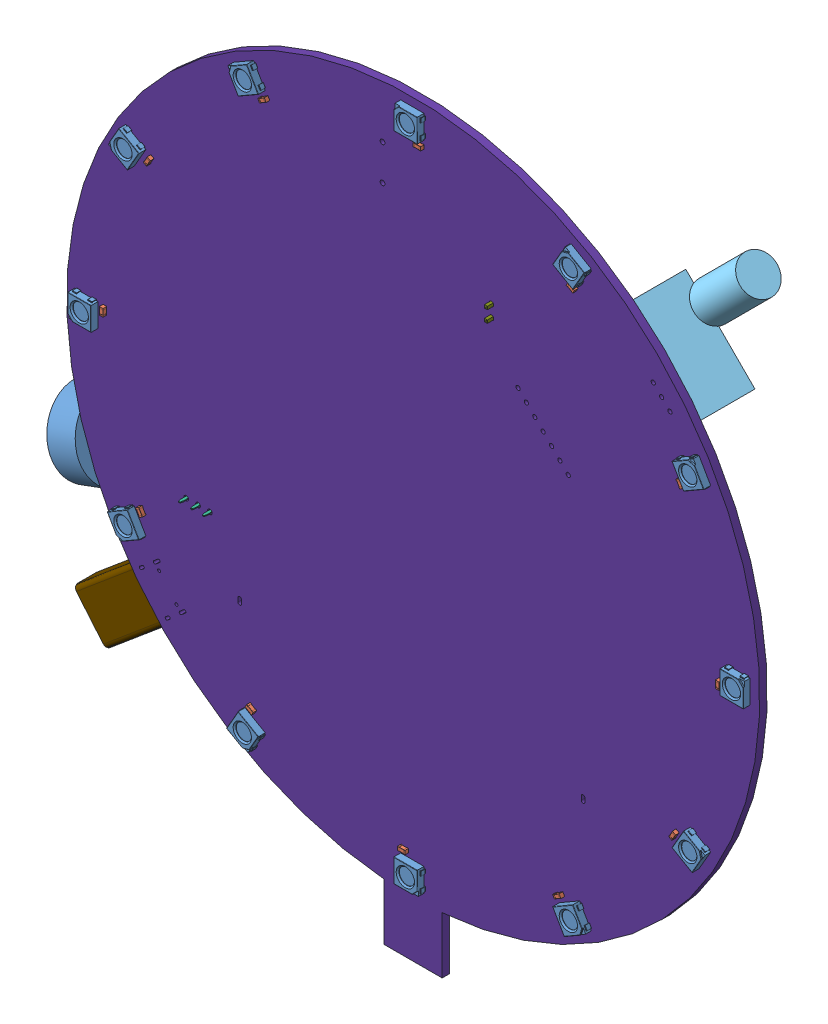
SolidWorks assembly Semafor_kompletni, configuration Výchozí. Lengths in mm.
Overall size (153.13 160.68 23.55).
171 component instances, 19 part files, 6 mates.
Components (placement in the parent):
- Semafor-1: Semafor [Výchozí] at origin size (148.79 160.68 22.8)
  - Semafor.step-1: Semafor.step [Výchozí] at origin size (148.79 160.68 22.8)
    - LED_WS2812B_PLCC4_5.0x5.0mm_P3.2mm.step-1: LED_WS2812B_PLCC4_5.0x5.0mm_P3.2mm.step [Výchozí] at (-39.4282 65.1 1.65) x (0.5 0.866025 0) z (0 0 1) size (5.4 5 1.6)
      - SOLID.step-1: SOLID.step [Výchozí] at origin size (5.4 5 1.6)
    - LED_WS2812B_PLCC4_5.0x5.0mm_P3.2mm.step-2: LED_WS2812B_PLCC4_5.0x5.0mm_P3.2mm.step [Výchozí] at (-30.05 100.1 1.65) x (0 1 0) z (0 0 1) size (5.4 5 1.6)
      - SOLID.step-1: SOLID.step [Výchozí] at origin size (5.4 5 1.6)
    - LED_WS2812B_PLCC4_5.0x5.0mm_P3.2mm.step-3: LED_WS2812B_PLCC4_5.0x5.0mm_P3.2mm.step [Výchozí] at (-170.05 100.1 1.65) x (0 -1 0) z (0 0 1) size (5.4 5 1.6)
      - SOLID.step-1: SOLID.step [Výchozí] at origin size (5.4 5 1.6)
    - C_0603_1608Metric.step-1: C_0603_1608Metric.step [Výchozí] at (-101.75 33.8 1.65) size (1.6 0.8 0.8)
      - SOLID-0.step-1: SOLID-0.step [Výchozí] at origin size (1.6 0.8 0.8)
    - C_0603_1608Metric.step-2: C_0603_1608Metric.step [Výchozí] at (-43.5875 65.6288 1.65) x (0.5 0.866025 0) z (0 0 1) size (1.6 0.8 0.8)
      - SOLID-0.step-1: SOLID-0.step [Výchozí] at origin size (1.6 0.8 0.8)
    - C_0603_1608Metric.step-3: C_0603_1608Metric.step [Výchozí] at (-134.4288 43.6125 1.65) x (0.866025 -0.5 0) z (0 0 1) size (1.6 0.8 0.8)
      - SOLID-0.step-1: SOLID-0.step [Výchozí] at origin size (1.6 0.8 0.8)
    - C_0603_1608Metric.step-4: C_0603_1608Metric.step [Výchozí] at (-166.15 101.75 1.65) x (0 -1 0) z (0 0 1) size (1.6 0.8 0.8)
      - SOLID-0.step-1: SOLID-0.step [Výchozí] at origin size (1.6 0.8 0.8)
    - LED_WS2812B_PLCC4_5.0x5.0mm_P3.2mm.step-4: LED_WS2812B_PLCC4_5.0x5.0mm_P3.2mm.step [Výchozí] at (-100.05 30.1 1.65) size (5.4 5 1.6)
      - SOLID.step-1: SOLID.step [Výchozí] at origin size (5.4 5 1.6)
    - C_0603_1608Metric.step-5: C_0603_1608Metric.step [Výchozí] at (-158.05 68.5 1.65) x (0.5 -0.866025 0) z (0 0 1) size (1.6 0.8 0.8)
      - SOLID-0.step-1: SOLID-0.step [Výchozí] at origin size (1.6 0.8 0.8)
    - C_0603_1608Metric.step-6: C_0603_1608Metric.step [Výchozí] at (-68.35 41.95 1.65) x (0.866025 0.5 0) z (0 0 1) size (1.6 0.8 0.8)
      - SOLID-0.step-1: SOLID-0.step [Výchozí] at origin size (1.6 0.8 0.8)
    - LED_WS2812B_PLCC4_5.0x5.0mm_P3.2mm.step-5: LED_WS2812B_PLCC4_5.0x5.0mm_P3.2mm.step [Výchozí] at (-100.05 170.1 1.65) x (-1 0 0) z (0 0 1) size (5.4 5 1.6)
      - SOLID.step-1: SOLID.step [Výchozí] at origin size (5.4 5 1.6)
    - LED_WS2812B_PLCC4_5.0x5.0mm_P3.2mm.step-6: LED_WS2812B_PLCC4_5.0x5.0mm_P3.2mm.step [Výchozí] at (-39.4282 135.1 1.65) x (-0.5 0.866025 0) z (0 0 1) size (5.4 5 1.6)
      - SOLID.step-1: SOLID.step [Výchozí] at origin size (5.4 5 1.6)
    - LED_WS2812B_PLCC4_5.0x5.0mm_P3.2mm.step-7: LED_WS2812B_PLCC4_5.0x5.0mm_P3.2mm.step [Výchozí] at (-160.6718 65.1 1.65) x (0.5 -0.866025 0) z (0 0 1) size (5.4 5 1.6)
      - SOLID.step-1: SOLID.step [Výchozí] at origin size (5.4 5 1.6)
    - LED_WS2812B_PLCC4_5.0x5.0mm_P3.2mm.step-8: LED_WS2812B_PLCC4_5.0x5.0mm_P3.2mm.step [Výchozí] at (-65.05 39.4782 1.65) x (0.866025 0.5 0) z (0 0 1) size (5.4 5 1.6)
      - SOLID.step-1: SOLID.step [Výchozí] at origin size (5.4 5 1.6)
    - C_0603_1608Metric.step-7: C_0603_1608Metric.step [Výchozí] at (-65.45 156.55 1.65) x (-0.866025 0.5 0) z (0 0 1) size (1.6 0.8 0.8)
      - SOLID-0.step-1: SOLID-0.step [Výchozí] at origin size (1.6 0.8 0.8)
    - C_0603_1608Metric.step-8: C_0603_1608Metric.step [Výchozí] at (-33.9 98.45 1.65) x (0 1 0) z (0 0 1) size (1.6 0.8 0.8)
      - SOLID-0.step-1: SOLID-0.step [Výchozí] at origin size (1.6 0.8 0.8)
    - C_0603_1608Metric.step-9: C_0603_1608Metric.step [Výchozí] at (-98.4 166.3 1.65) x (-1 0 0) z (0 0 1) size (1.6 0.8 0.8)
      - SOLID-0.step-1: SOLID-0.step [Výchozí] at origin size (1.6 0.8 0.8)
    - LED_WS2812B_PLCC4_5.0x5.0mm_P3.2mm.step-9: LED_WS2812B_PLCC4_5.0x5.0mm_P3.2mm.step [Výchozí] at (-160.6718 135.1 1.65) x (-0.5 -0.866025 0) z (0 0 1) size (5.4 5 1.6)
      - SOLID.step-1: SOLID.step [Výchozí] at origin size (5.4 5 1.6)
    - LED_WS2812B_PLCC4_5.0x5.0mm_P3.2mm.step-10: LED_WS2812B_PLCC4_5.0x5.0mm_P3.2mm.step [Výchozí] at (-65.05 160.7218 1.65) x (-0.866025 0.5 0) z (0 0 1) size (5.4 5 1.6)
      - SOLID.step-1: SOLID.step [Výchozí] at origin size (5.4 5 1.6)
    - C_0603_1608Metric.step-10: C_0603_1608Metric.step [Výchozí] at (-156.35 134.6 1.65) x (-0.5 -0.866025 0) z (0 0 1) size (1.6 0.8 0.8)
      - SOLID-0.step-1: SOLID-0.step [Výchozí] at origin size (1.6 0.8 0.8)
    - LED_WS2812B_PLCC4_5.0x5.0mm_P3.2mm.step-11: LED_WS2812B_PLCC4_5.0x5.0mm_P3.2mm.step [Výchozí] at (-135.05 160.7218 1.65) x (-0.866025 -0.5 0) z (0 0 1) size (5.4 5 1.6)
      - SOLID.step-1: SOLID.step [Výchozí] at origin size (5.4 5 1.6)
    - C_0603_1608Metric.step-11: C_0603_1608Metric.step [Výchozí] at (-131.65 158.3 1.65) x (-0.866025 -0.5 0) z (0 0 1) size (1.6 0.8 0.8)
      - SOLID-0.step-1: SOLID-0.step [Výchozí] at origin size (1.6 0.8 0.8)
    - C_0603_1608Metric.step-12: C_0603_1608Metric.step [Výchozí] at (-42.05 131.8 1.65) x (-0.5 0.866025 0) z (0 0 1) size (1.6 0.8 0.8)
      - SOLID-0.step-1: SOLID-0.step [Výchozí] at origin size (1.6 0.8 0.8)
    - LED_WS2812B_PLCC4_5.0x5.0mm_P3.2mm.step-12: LED_WS2812B_PLCC4_5.0x5.0mm_P3.2mm.step [Výchozí] at (-135.05 39.4782 1.65) x (0.866025 -0.5 0) z (0 0 1) size (5.4 5 1.6)
      - SOLID.step-1: SOLID.step [Výchozí] at origin size (5.4 5 1.6)
    - R_0603_1608Metric.step-1: R_0603_1608Metric.step [Výchozí] at (-119.75 147.925 -0.05) x (0 -1 0) z (0 0 -1) size (1.6 0.8 0.45)
      - SOLID-1.step-1: SOLID-1.step [Výchozí] at origin size (1.6 0.8 0.45)
    - R_0603_1608Metric.step-2: R_0603_1608Metric.step [Výchozí] at (-115.95 147.9 -0.05) x (0 -1 0) z (0 0 -1) size (1.6 0.8 0.45)
      - SOLID-1.step-1: SOLID-1.step [Výchozí] at origin size (1.6 0.8 0.45)
    - D_SOD-123.step-1: D_SOD-123.step [Výchozí] at (-130.0125 82.075 -0.05) x (-1 0 0) z (0 0 -1) size (3.8 1.6 1.25)
      - SOLID-2.step-1: SOLID-2.step [Výchozí] at origin size (3.8 1.6 1.25)
    - E22_900T22D.step-1: E22_900T22D.step [Výchozí] at (-60.45 137.7711 -0.05) x (-0.707107 -0.707107 0) z (0 0 -1) size (50 21 17.3)
      - SOLID-3.step-1: SOLID-3.step [Výchozí] at origin size (50 21 17.3)
    - D_SOD-123.step-2: D_SOD-123.step [Výchozí] at (-96.1 29.05 -0.05) x (0 -1 0) z (0 0 -1) size (3.8 1.6 1.25)
      - SOLID-2.step-1: SOLID-2.step [Výchozí] at origin size (3.8 1.6 1.25)
    - PinSocket_1x03_P2.54mm_Vertical.step-1: PinSocket_1x03_P2.54mm_Vertical.step [Výchozí] at (-143.675 75.375 -0.05) x (0 1 0) z (0 0 -1) size (2.54 7.62 10.1)
      - SOLID-4.step-1: SOLID-4.step [Výchozí] at origin size (2.54 7.62 10.1)
    - D_SOD-323.step-1: D_SOD-323.step [Výchozí] at (-142.6 58.8 -0.05) x (0.642788 -0.766044 0) z (0 0 -1) size (2.5 1.25 1.1)
      - SOLID-5.step-1: SOLID-5.step [Výchozí] at origin size (2.5 1.25 1.1)
    - C_0603_1608Metric.step-13: C_0603_1608Metric.step [Výchozí] at (-158.9591 131.0993 -0.05) x (-0.939693 0.34202 0) z (0 0 -1) size (1.6 0.8 0.8)
      - SOLID-0.step-1: SOLID-0.step [Výchozí] at origin size (1.6 0.8 0.8)
    - R_0603_1608Metric.step-3: R_0603_1608Metric.step [Výchozí] at (-83.3756 132.275 -0.05) x (-1 0 0) z (0 0 -1) size (1.6 0.8 0.45)
      - SOLID-1.step-1: SOLID-1.step [Výchozí] at origin size (1.6 0.8 0.45)
    - R_0603_1608Metric.step-4: R_0603_1608Metric.step [Výchozí] at (-118.05 147.9 -0.05) x (0 -1 0) z (0 0 -1) size (1.6 0.8 0.45)
      - SOLID-1.step-1: SOLID-1.step [Výchozí] at origin size (1.6 0.8 0.45)
    - R_0603_1608Metric.step-5: R_0603_1608Metric.step [Výchozí] at (-116.95 136.3 -0.05) x (0 -1 0) z (0 0 -1) size (1.6 0.8 0.45)
      - SOLID-1.step-1: SOLID-1.step [Výchozí] at origin size (1.6 0.8 0.45)
    - C_0805_2012Metric.step-1: C_0805_2012Metric.step [Výchozí] at (-152.9591 126.5493 -0.05) x (0.939693 -0.34202 0) z (0 0 -1) size (2 1.25 1.25)
      - SOLID-6.step-1: SOLID-6.step [Výchozí] at origin size (2 1.25 1.25)
    - LED_0603_1608Metric.step-1: LED_0603_1608Metric.step [Výchozí] at (-147.525 84.025 -0.05) x (-1 0 0) z (0 0 -1) size (1.6 0.8 1.1)
      - SOLID-7.step-1: SOLID-7.step [Výchozí] at origin size (1.6 0.8 1.1)
    - SOT-23.step-1: SOT-23.step [Výchozí] at (-83.3256 136.55 -0.05) x (0 1 0) z (0 0 -1) size (2.5 3 1.2)
      - SOLID-8.step-1: SOLID-8.step [Výchozí] at origin size (2.5 3 1.2)
    - SOT-23.step-2: SOT-23.step [Výchozí] at (-146.9091 122.0993 -0.05) x (0.939693 -0.34202 0) z (0 0 -1) size (2.5 3 1.2)
      - SOLID-8.step-1: SOLID-8.step [Výchozí] at origin size (2.5 3 1.2)
    - R_0603_1608Metric.step-6: R_0603_1608Metric.step [Výchozí] at (-120.725 43.975 -0.05) x (-1 0 0) z (0 0 -1) size (1.6 0.8 0.45)
      - SOLID-1.step-1: SOLID-1.step [Výchozí] at origin size (1.6 0.8 0.45)
    - C_0805_2012Metric.step-2: C_0805_2012Metric.step [Výchozí] at (-159.7591 129.0993 -0.05) x (-0.939693 0.34202 0) z (0 0 -1) size (2 1.25 1.25)
      - SOLID-6.step-1: SOLID-6.step [Výchozí] at origin size (2 1.25 1.25)
    - R_0603_1608Metric.step-7: R_0603_1608Metric.step [Výchozí] at (-120.15 136.3 -0.05) x (0 -1 0) z (0 0 -1) size (1.6 0.8 0.45)
      - SOLID-1.step-1: SOLID-1.step [Výchozí] at origin size (1.6 0.8 0.45)
    - D_SOD-323.step-2: D_SOD-323.step [Výchozí] at (-147.5 62.875 -0.05) x (-0.766044 -0.642788 0) z (0 0 -1) size (2.5 1.25 1.1)
      - SOLID-5.step-1: SOLID-5.step [Výchozí] at origin size (2.5 1.25 1.1)
    - C_0805_2012Metric.step-3: C_0805_2012Metric.step [Výchozí] at (-128.3875 78.75 -0.05) x (0 -1 0) z (0 0 -1) size (2 1.25 1.25)
      - SOLID-6.step-1: SOLID-6.step [Výchozí] at origin size (2 1.25 1.25)
    - R_0603_1608Metric.step-8: R_0603_1608Metric.step [Výchozí] at (-143.0091 117.4493 -0.05) x (0.939693 -0.34202 0) z (0 0 -1) size (1.6 0.8 0.45)
      - SOLID-1.step-1: SOLID-1.step [Výchozí] at origin size (1.6 0.8 0.45)
    - LED_0603_1608Metric.step-2: LED_0603_1608Metric.step [Výchozí] at (-109.425 43.2125 -0.05) x (0 -1 0) z (0 0 -1) size (1.6 0.8 1.1)
      - SOLID-7.step-1: SOLID-7.step [Výchozí] at origin size (1.6 0.8 1.1)
    - R_0603_1608Metric.step-9: R_0603_1608Metric.step [Výchozí] at (-135.1875 77.025 -0.05) x (0 1 0) z (0 0 -1) size (1.6 0.8 0.45)
      - SOLID-1.step-1: SOLID-1.step [Výchozí] at origin size (1.6 0.8 0.45)
    - USB_C.step-1: USB_C.step [Výchozí] at (-154.7 55.1 -0.05) x (-0.766044 -0.642788 0) z (0 0 -1) size (7.5 9 3.5)
      - SOLID-9.step-1: SOLID-9.step [Výchozí] at origin size (7.5 9 3.5)
    - Battery_pack.step-1: Battery_pack.step [Výchozí] at (-99.9 62.1 -0.05) x (-1 0 0) z (0 0 -1) size (77 21 19.5)
      - SOLID-10.step-1: SOLID-10.step [Výchozí] at origin size (77 21 19.5)
    - LED_0603_1608Metric.step-3: LED_0603_1608Metric.step [Výchozí] at (-107.575 43.225 -0.05) x (0 -1 0) z (0 0 -1) size (1.6 0.8 1.1)
      - SOLID-7.step-1: SOLID-7.step [Výchozí] at origin size (1.6 0.8 1.1)
    - R_0603_1608Metric.step-10: R_0603_1608Metric.step [Výchozí] at (-144.1125 87.05 -0.05) x (1 0 0) z (0 0 -1) size (1.6 0.8 0.45)
      - SOLID-1.step-1: SOLID-1.step [Výchozí] at origin size (1.6 0.8 0.45)
    - D_SOD-123.step-3: D_SOD-123.step [Výchozí] at (-117.975 155.17 -0.05) x (-1 0 0) z (0 0 -1) size (3.8 1.6 1.25)
      - SOLID-2.step-1: SOLID-2.step [Výchozí] at origin size (3.8 1.6 1.25)
    - R_0603_1608Metric.step-11: R_0603_1608Metric.step [Výchozí] at (-114.175 160.345 -0.05) x (0 -1 0) z (0 0 -1) size (1.6 0.8 0.45)
      - SOLID-1.step-1: SOLID-1.step [Výchozí] at origin size (1.6 0.8 0.45)
    - R_0603_1608Metric.step-12: R_0603_1608Metric.step [Výchozí] at (-150.9091 118.3743 -0.05) x (-0.34202 -0.939693 0) z (0 0 -1) size (1.6 0.8 0.45)
      - SOLID-1.step-1: SOLID-1.step [Výchozí] at origin size (1.6 0.8 0.45)
    - D_SOD-323.step-3: D_SOD-323.step [Výchozí] at (-98.4 29.65 -0.05) x (0 1 0) z (0 0 -1) size (2.5 1.25 1.1)
      - SOLID-5.step-1: SOLID-5.step [Výchozí] at origin size (2.5 1.25 1.1)
    - SOIC-14_3.9x8.7mm_P1.27mm.step-1: SOIC-14_3.9x8.7mm_P1.27mm.step [Výchozí] at (-118.5 142.1 -0.05) x (0 -1 0) z (0 0 -1) size (6 8.7 1.75)
      - SOLID-11.step-1: SOLID-11.step [Výchozí] at origin size (6 8.7 1.75)
    - C_0603_1608Metric.step-14: C_0603_1608Metric.step [Výchozí] at (-124.55 142.3493 -0.05) x (0 -1 0) z (0 0 -1) size (1.6 0.8 0.8)
      - SOLID-0.step-1: SOLID-0.step [Výchozí] at origin size (1.6 0.8 0.8)
    - R_0603_1608Metric.step-13: R_0603_1608Metric.step [Výchozí] at (-147.4841 125.4493 -0.05) x (0.939693 -0.34202 0) z (0 0 -1) size (1.6 0.8 0.45)
      - SOLID-1.step-1: SOLID-1.step [Výchozí] at origin size (1.6 0.8 0.45)
    - C_0805_2012Metric.step-4: C_0805_2012Metric.step [Výchozí] at (-126.5 142.3993 -0.05) x (0 -1 0) z (0 0 -1) size (2 1.25 1.25)
      - SOLID-6.step-1: SOLID-6.step [Výchozí] at origin size (2 1.25 1.25)
    - R_0603_1608Metric.step-14: R_0603_1608Metric.step [Výchozí] at (-139.1625 81.2 -0.05) x (0 -1 0) z (0 0 -1) size (1.6 0.8 0.45)
      - SOLID-1.step-1: SOLID-1.step [Výchozí] at origin size (1.6 0.8 0.45)
    - R_0603_1608Metric.step-15: R_0603_1608Metric.step [Výchozí] at (-132.6875 77.875 -0.05) x (1 0 0) z (0 0 -1) size (1.6 0.8 0.45)
      - SOLID-1.step-1: SOLID-1.step [Výchozí] at origin size (1.6 0.8 0.45)
    - SOT-23.step-3: SOT-23.step [Výchozí] at (-118.675 160.445 -0.05) x (-1 0 0) z (0 0 -1) size (2.5 3 1.2)
      - SOLID-8.step-1: SOLID-8.step [Výchozí] at origin size (2.5 3 1.2)
    - R_0402_1005Metric.step-1: R_0402_1005Metric.step [Výchozí] at (-150.45 61 -0.05) x (0.766044 0.642788 0) z (0 0 -1) size (1 0.5 0.35)
      - SOLID-12.step-1: SOLID-12.step [Výchozí] at origin size (1 0.5 0.35)
    - C_0805_2012Metric.step-5: C_0805_2012Metric.step [Výchozí] at (-114.675 48.525 -0.05) x (-1 0 0) z (0 0 -1) size (2 1.25 1.25)
      - SOLID-6.step-1: SOLID-6.step [Výchozí] at origin size (2 1.25 1.25)
    - R_0603_1608Metric.step-16: R_0603_1608Metric.step [Výchozí] at (-152.1341 114.7493 -0.05) x (-0.34202 -0.939693 0) z (0 0 -1) size (1.6 0.8 0.45)
      - SOLID-1.step-1: SOLID-1.step [Výchozí] at origin size (1.6 0.8 0.45)
    - C_0603_1608Metric.step-15: C_0603_1608Metric.step [Výchozí] at (-78.4756 143.175 -0.05) x (0 -1 0) z (0 0 -1) size (1.6 0.8 0.8)
      - SOLID-0.step-1: SOLID-0.step [Výchozí] at origin size (1.6 0.8 0.8)
    - C_0805_2012Metric.step-6: C_0805_2012Metric.step [Výchozí] at (-120.625 46.525 -0.05) x (-1 0 0) z (0 0 -1) size (2 1.25 1.25)
      - SOLID-6.step-1: SOLID-6.step [Výchozí] at origin size (2 1.25 1.25)
    - R_0603_1608Metric.step-17: R_0603_1608Metric.step [Výchozí] at (-115.3 136.3 -0.05) x (0 1 0) z (0 0 -1) size (1.6 0.8 0.45)
      - SOLID-1.step-1: SOLID-1.step [Výchozí] at origin size (1.6 0.8 0.45)
    - SOT-23-5.step-1: SOT-23-5.step [Výchozí] at (-135.2875 81.1 -0.05) x (-1 0 0) z (0 0 -1) size (2.8 2.9 1.55)
      - SOLID-13.step-1: SOLID-13.step [Výchozí] at origin size (2.8 2.9 1.55)
    - R_0402_1005Metric.step-2: R_0402_1005Metric.step [Výchozí] at (-148.35 58.75 -0.05) x (0.766044 0.642788 0) z (0 0 -1) size (1 0.5 0.35)
      - SOLID-12.step-1: SOLID-12.step [Výchozí] at origin size (1 0.5 0.35)
    - C_0805_2012Metric.step-7: C_0805_2012Metric.step [Výchozí] at (-136.7875 84.075 -0.05) x (1 0 0) z (0 0 -1) size (2 1.25 1.25)
      - SOLID-6.step-1: SOLID-6.step [Výchozí] at origin size (2 1.25 1.25)
    - PinHeader_1x02_P2.54mm_Vertical.step-1: PinHeader_1x02_P2.54mm_Vertical.step [Výchozí] at (-83.2244 144.25 -0.05) x (-1 0 0) z (0 0 -1) size (2.54 5.08 11.54)
      - SOLID-14.step-1: SOLID-14.step [Výchozí] at origin size (2.54 5.08 11.54)
    - D_SOD-323.step-4: D_SOD-323.step [Výchozí] at (-146.2 61.275 -0.05) x (-0.766044 -0.642788 0) z (0 0 -1) size (2.5 1.25 1.1)
      - SOLID-5.step-1: SOLID-5.step [Výchozí] at origin size (2.5 1.25 1.1)
    - LED_0603_1608Metric.step-4: LED_0603_1608Metric.step [Výchozí] at (-147.5125 87.075 -0.05) x (-1 0 0) z (0 0 -1) size (1.6 0.8 1.1)
      - SOLID-7.step-1: SOLID-7.step [Výchozí] at origin size (1.6 0.8 1.1)
    - R_0603_1608Metric.step-18: R_0603_1608Metric.step [Výchozí] at (-156.1591 128.8493 -0.05) x (0.939693 -0.34202 0) z (0 0 -1) size (1.6 0.8 0.45)
      - SOLID-1.step-1: SOLID-1.step [Výchozí] at origin size (1.6 0.8 0.45)
    - R_0603_1608Metric.step-19: R_0603_1608Metric.step [Výchozí] at (-144.15 84.05 -0.05) x (1 0 0) z (0 0 -1) size (1.6 0.8 0.45)
      - SOLID-1.step-1: SOLID-1.step [Výchozí] at origin size (1.6 0.8 0.45)
    - R_0603_1608Metric.step-20: R_0603_1608Metric.step [Výchozí] at (-110.275 40.775 -0.05) x (1 0 0) z (0 0 -1) size (1.6 0.8 0.45)
      - SOLID-1.step-1: SOLID-1.step [Výchozí] at origin size (1.6 0.8 0.45)
    - D_SOD-123.step-4: D_SOD-123.step [Výchozí] at (-144.6 55.65 -0.05) x (-0.766044 -0.642788 0) z (0 0 -1) size (3.8 1.6 1.25)
      - SOLID-2.step-1: SOLID-2.step [Výchozí] at origin size (3.8 1.6 1.25)
    - SOT-23.step-4: SOT-23.step [Výchozí] at (-143.8591 114.7993 -0.05) x (0.939693 -0.34202 0) z (0 0 -1) size (2.5 3 1.2)
      - SOLID-8.step-1: SOLID-8.step [Výchozí] at origin size (2.5 3 1.2)
    - R_0603_1608Metric.step-21: R_0603_1608Metric.step [Výchozí] at (-155.1091 131.9243 -0.05) x (-0.34202 -0.939693 0) z (0 0 -1) size (1.6 0.8 0.45)
      - SOLID-1.step-1: SOLID-1.step [Výchozí] at origin size (1.6 0.8 0.45)
    - R_0603_1608Metric.step-22: R_0603_1608Metric.step [Výchozí] at (-118.55 136.3 -0.05) x (0 -1 0) z (0 0 -1) size (1.6 0.8 0.45)
      - SOLID-1.step-1: SOLID-1.step [Výchozí] at origin size (1.6 0.8 0.45)
    - R_0603_1608Metric.step-23: R_0603_1608Metric.step [Výchozí] at (-121.75 136.2993 -0.05) x (0 -1 0) z (0 0 -1) size (1.6 0.8 0.45)
      - SOLID-1.step-1: SOLID-1.step [Výchozí] at origin size (1.6 0.8 0.45)
    - D_SOD-123.step-5: D_SOD-123.step [Výchozí] at (-74.5506 143.175 -0.05) x (0 -1 0) z (0 0 -1) size (3.8 1.6 1.25)
      - SOLID-2.step-1: SOLID-2.step [Výchozí] at origin size (3.8 1.6 1.25)
    - Semafor PCB.step-1: Semafor PCB.step [Výchozí] at origin size (148.79 160.68 1.6)
- USB_cable-1: USB_cable [Výchozí] at (-163.701 47.5472 -4.8) x (0.766044 0.642788 0) z (0 0 1) size (20 11 6)
- Button-2: Button [Výchozí] at (-162.6501 76.4818 -4.5) x (-0.347544 0.937664 0) z (0 0 1) size (17 22 17)
Mates (geometry in assembly coordinates):
- Tečná1: tangent: plane of assembly; face of Semafor-1/Semafor.step-1/USB_C.step-1/SOLID-9.step-1; plane of USB_cable-1 through (-156.7582 57.9419 -1.05) normal (0 0 1)
- Tečná2: tangent: plane of assembly; face of Semafor-1/Semafor.step-1/USB_C.step-1/SOLID-9.step-1; plane of USB_cable-1 through (-156.7582 57.9419 -1.05) normal (-0.642788 0.766044 0)
- Tečná3: tangent: plane of assembly; face of Semafor-1/Semafor.step-1/USB_C.step-1/SOLID-9.step-1; plane of USB_cable-1 through (-161.108 56.9028 1.2) normal (0.766044 0.642788 0)
- Sjednocená1: coincident anti-aligned: plane of Semafor-1/Semafor.step-1/Semafor PCB.step-1 through (-100.0019 93.8452 0) normal (0 0 -1); plane of Button-2 through (-167.5104 68.0148 0) normal (0 0 1)
- Tečná4: tangent anti-aligned: cylinder of Semafor-1/Semafor.step-1/Semafor PCB.step-1 through (-100 99.9315 0) axis (0 0 -1) radius 74.3945; plane of Button-2 through (-169.6826 73.8752 -4.5) normal (0.937664 0.347544 0)
- Zámek1: lock: unknown of Semafor-1/Semafor.step-1/USB_C.step-1/SOLID-9.step-1; unknown of Button-2
